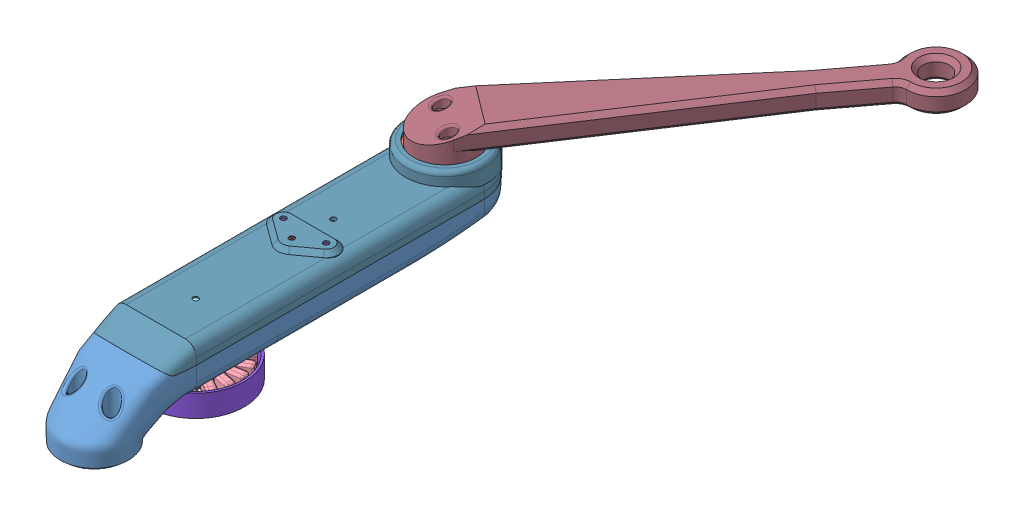
SolidWorks assembly Detailed upper leg module assembly new, configuration Default. Lengths in mm.
Overall size (146.19 56.44 322.34).
28 component instances, 17 part files, 42 mates.
Components (placement in the parent):
- upper limb base-1: upper limb base [Default] at (70.7092 92.7911 149.0007) size (42.52 37.51 198.25)
  - upper leg module shell base-1: upper leg module shell base [Default] x (-1 0 0) z (0 0 -1) size (37.02 37.51 198.25)
  - bearing 32x25x4mm-1: bearing 32x25x4mm [Default] at (0 0.5 -61) x (0.90658 0 0.422034) z (-0.422034 0 0.90658) size (32 4 32)
  - bearing 8mm x 3mm x 3mm-1: bearing 8mm x 3mm x 3mm [Default] at (0 -1.5 8.9) x (1 0 0) z (0 -1 0) size (7.96 7.96 3)
- motor rotor-1: motor rotor [Default] at (70.7092 85.0911 201.8007) x (0 0 -1) z (-1 0 0) size (40 13.5 39.72)
- motor assembly-2: motor assembly [Default] at (70.7092 72.4911 201.8007) x (-0.761097 0 -0.648639) z (-0.648639 0 0.761097) size (16.67 33.4 16.67)
  - motor shaft-1: motor shaft [Default] x (1 0 0) z (0 -1 0) size (3.99 3.99 33.4)
  - motor pulley-1: motor pulley [Default] at (0 -20.1 0) x (1 0 0) z (0 -1 0) size (8.98 9.1 6.7)
  - encoder wheel mount-1: encoder wheel mount [Default] at (0 -28.3 0) x (-0.562764 0 0.826618) z (-0.826618 0 -0.562764) size (12 5.96 12)
- motor stator-1: motor stator [Default] at (70.7092 85.0911 201.8007) x (0.629554 0 -0.776957) z (0 -1 0) size (44.35 44.35 16.24)
- B18.6.7M - M3 x 0.5 x 5 Type I Cross Recessed FHMS --5S-1: B18.6.7M - M3 x 0.5 x 5 Type I Cross Recessed FHMS --5S [B18.6.7M - M3 x 0.5 x 5 Type I Cross Recessed FHMS --5S] at (83.2092 94.5911 201.8007) x (0 -1 0) z (-0.166423 0 0.986054) size (5 5.5 5.5)
- B18.6.7M - M3 x 0.5 x 5 Type I Cross Recessed FHMS --5S-2: B18.6.7M - M3 x 0.5 x 5 Type I Cross Recessed FHMS --5S [B18.6.7M - M3 x 0.5 x 5 Type I Cross Recessed FHMS --5S] at (70.7092 94.5911 214.3007) x (0 -1 0) z (0.029806 0 0.999556) size (5 5.5 5.5)
- B18.6.7M - M3 x 0.5 x 5 Type I Cross Recessed FHMS --5S-3: B18.6.7M - M3 x 0.5 x 5 Type I Cross Recessed FHMS --5S [B18.6.7M - M3 x 0.5 x 5 Type I Cross Recessed FHMS --5S] at (58.2092 94.5911 201.8007) x (0 -1 0) z (0.999629 0 -0.027231) size (5 5.5 5.5)
- B18.6.7M - M3 x 0.5 x 5 Type I Cross Recessed FHMS --5S-4: B18.6.7M - M3 x 0.5 x 5 Type I Cross Recessed FHMS --5S [B18.6.7M - M3 x 0.5 x 5 Type I Cross Recessed FHMS --5S] at (70.7092 94.5911 189.3007) x (0 -1 0) z (-0.93368 0 0.358107) size (5 5.5 5.5)
- centre pulley-1: centre pulley [Default] at (66.4357 80.4446 131.9015) x (0.990944 0 0.134278) z (-0.134278 0 0.990944) size (30 19 30)
  - transmission pulley centre-1: transmission pulley centre [Default] at (7.726 11.8465 25.1899) size (30 6.8 30)
  - centre pulley-1: centre pulley [Default] at (7.726 25.3465 25.1899) x (0.694658 0 -0.71934) z (0 -1 0) size (8.98 9.1 19)
- transmission pulley output-1: transmission pulley output [Default] at (70.7092 97.7911 88.0007) x (-0.799532 0 -0.600624) z (0.600624 0 -0.799532) size (29 16.4 29)
- lower leg-1: lower leg [Default] at (118.7591 125.2911 24.0382) x (0.600624 0 -0.799532) z (-0.799532 0 -0.600624) size (187 20 27)
- upper leg module cover-1: upper leg module cover [Default] at (70.7092 98.7911 142.6299) x (0 0 1) z (-1 0 0) size (170.23 17.96 37.06)
- bearing 32x25x4mm-1: bearing 32x25x4mm [Default] at (70.7092 107.2911 88.0007) size (32 4 32)
- bearing 8mm x 3mm x 3mm-1: bearing 8mm x 3mm x 3mm [Default] at (70.7092 107.2911 157.9007) x (1 0 0) z (0 -1 0) size (7.96 7.96 3)
- transmission belt tension roller-1: transmission belt tension roller [Default] at (60.9592 99.8911 152.0007) x (0.454066 0 0.890968) z (-0.890968 0 0.454066) size (10 4 10)
- bearing 7mm x 3mm x 3mm-2: bearing 7mm x 3mm x 3mm [Default] at (60.9592 103.8911 152.0007) x (0.030533 0 0.999534) z (0 -1 0) size (7 7 3)
- transmission belt tension roller-2: transmission belt tension roller [Default] at (80.4592 99.8911 152.0007) x (0.177081 0 -0.984196) z (0.984196 0 0.177081) size (10 4 10)
- bearing 7mm x 3mm x 3mm-3: bearing 7mm x 3mm x 3mm [Default] at (80.4592 103.8911 152.0007) x (0 0 -1) z (0 -1 0) size (7 7 3)
- flat head screw_am-1: flat head screw_am [B18.6.7M - M3 x 0.5 x 8 Type I Cross Recessed FHMS --8S] at (60.9592 100.0411 152.0007) x (0 1 0) z (0.851744 0 -0.523958) size (8 5.5 5.5)
- flat head screw_am-2: flat head screw_am [B18.6.7M - M3 x 0.5 x 8 Type I Cross Recessed FHMS --8S] at (80.4592 100.0411 152.0007) x (0 1 0) z (0.851744 0 -0.523958) size (8 5.5 5.5)
Mates (geometry in assembly coordinates):
- Concentric1: concentric aligned: cylinder of upper limb base-1/upper leg module shell base-1 through (70.7092 93.0911 201.8007) axis (0 -1 0) radius 15.25; cylinder of motor rotor-1 through (70.7092 92.5911 201.8007) axis (0 -1 0) radius 15
- Concentric2: concentric anti-aligned: cylinder of upper limb base-1/upper leg module shell base-1 through (70.7092 64.5911 189.3007) axis (0 1 0) radius 1.6; cylinder of motor rotor-1 through (70.7092 92.5911 189.3007) axis (0 -1 0) radius 2
- Coincident1: coincident anti-aligned: plane of upper limb base-1/upper leg module shell base-1 through (70.7092 92.5911 201.8007) normal (0 -1 0); plane of motor rotor-1 through (70.7092 92.5911 201.8007) normal (0 1 0)
- Concentric3: concentric aligned: line of motor rotor-1 through (70.7092 92.5911 201.8007) axis (0 -1 0); cylinder of motor assembly-2/motor shaft-1 through (70.7092 105.8911 201.8007) axis (0 -1 0) radius 1.995
- Coincident2: coincident anti-aligned: plane of motor rotor-1 through (70.7092 92.5911 201.8007) normal (0 1 0); plane of motor assembly-2/motor pulley-1 through (70.7092 92.5911 201.8007) normal (0 -1 0)
- Concentric4: concentric aligned: cylinder of motor assembly-2/motor shaft-1 through (70.7092 105.8911 201.8007) axis (0 -1 0) radius 1.995; cylinder of motor stator-1 through (70.7092 75.0911 201.8007) axis (0 -1 0) radius 2
- Coincident3: coincident aligned: plane of motor rotor-1 through (70.7092 85.0911 201.8007) normal (0 1 0); plane of motor stator-1 through (70.7092 85.0911 201.8007) normal (0 1 0)
- Concentric5: concentric anti-aligned: cylinder of motor rotor-1 through (70.7092 92.5911 189.3007) axis (0 -1 0) radius 2; cylinder of B18.6.7M - M3 x 0.5 x 5 Type I Cross Recessed FHMS --5S-4 through (70.7092 100.9411 189.3007) axis (0 1 0) radius 1.5
- Concentric6: concentric anti-aligned: cylinder of motor rotor-1 through (58.2092 92.5911 201.8007) axis (0 -1 0) radius 2; cylinder of B18.6.7M - M3 x 0.5 x 5 Type I Cross Recessed FHMS --5S-3 through (58.2092 100.9411 201.8007) axis (0 1 0) radius 1.5
- Concentric7: concentric anti-aligned: cylinder of motor rotor-1 through (70.7092 92.5911 214.3007) axis (0 -1 0) radius 2; cylinder of B18.6.7M - M3 x 0.5 x 5 Type I Cross Recessed FHMS --5S-2 through (70.7092 100.9411 214.3007) axis (0 1 0) radius 1.5
- Concentric8: concentric anti-aligned: cylinder of motor rotor-1 through (83.2092 92.5911 201.8007) axis (0 -1 0) radius 2; cylinder of B18.6.7M - M3 x 0.5 x 5 Type I Cross Recessed FHMS --5S-1 through (83.2092 100.9411 201.8007) axis (0 1 0) radius 1.5
- Coincident4: coincident aligned: plane of upper limb base-1/upper leg module shell base-1 through (70.7092 94.5911 201.8007) normal (0 1 0); plane of B18.6.7M - M3 x 0.5 x 5 Type I Cross Recessed FHMS --5S-4 through (70.7092 94.5911 189.3007) normal (0 1 0)
- Coincident5: coincident aligned: plane of upper limb base-1/upper leg module shell base-1 through (70.7092 94.5911 201.8007) normal (0 1 0); plane of B18.6.7M - M3 x 0.5 x 5 Type I Cross Recessed FHMS --5S-3 through (58.2092 94.5911 201.8007) normal (0 1 0)
- Coincident6: coincident aligned: plane of upper limb base-1/upper leg module shell base-1 through (70.7092 94.5911 201.8007) normal (0 1 0); plane of B18.6.7M - M3 x 0.5 x 5 Type I Cross Recessed FHMS --5S-1 through (83.2092 94.5911 201.8007) normal (0 1 0)
- Coincident7: coincident aligned: plane of upper limb base-1/upper leg module shell base-1 through (70.7092 94.5911 201.8007) normal (0 1 0); plane of B18.6.7M - M3 x 0.5 x 5 Type I Cross Recessed FHMS --5S-2 through (70.7092 94.5911 214.3007) normal (0 1 0)
- Concentric9: concentric anti-aligned: line of upper limb base-1/bearing 8mm x 3mm x 3mm-1 through (70.7092 91.0911 157.9007) axis (0 -1 0); cylinder of centre pulley-1/centre pulley-1 through (70.7092 89.2911 157.9007) axis (0 1 0) radius 1.995
- Coincident9: coincident anti-aligned: plane of upper limb base-1/bearing 8mm x 3mm x 3mm-1 through (70.7092 91.2911 157.9007) normal (0 1 0); plane of centre pulley-1/centre pulley-1 through (70.7092 91.2911 157.9007) normal (0 -1 0)
- Concentric11: concentric anti-aligned: cylinder of upper limb base-1/bearing 32x25x4mm-1 through (70.7092 97.2911 88.0007) axis (0 -1 0) radius 12.5; cylinder of transmission pulley output-1 through (70.7092 93.4411 88.0007) axis (0 1 0) radius 12.575
- Coincident12: coincident anti-aligned: plane of upper limb base-1/bearing 32x25x4mm-1 through (70.7092 97.2911 88.0007) normal (0 1 0); plane of transmission pulley output-1 through (70.7092 97.2911 88.0007) normal (0 -1 0)
- Coincident18: coincident anti-aligned: plane of transmission pulley output-1 through (80.1125 93.4411 83.808) normal (-0.799532 0 -0.600624); plane of lower leg-1 through (70.2022 105.2911 97.0003) normal (0.799532 0 0.600624)
- Coincident19: coincident anti-aligned: plane of transmission pulley output-1 through (61.3059 93.4411 92.1934) normal (0.600624 0 -0.799532); plane of lower leg-1 through (62.5052 105.2911 93.0943) normal (-0.600624 0 0.799532)
- Concentric12: concentric aligned: circle of upper limb base-1/bearing 32x25x4mm-1; cylinder of upper leg module cover-1 through (70.7092 87.7911 88.0007) axis (0 1 0) radius 14.25
- Coincident20: coincident aligned: plane of upper limb base-1/upper leg module shell base-1 through (89.2092 86.7911 109.0007) normal (1 0 0); plane of upper leg module cover-1 through (89.2092 106.7911 219.9999) normal (1 0 0)
- Coincident24: coincident anti-aligned: plane of upper leg module cover-1 through (70.7092 107.2911 157.9007) normal (0 -1 0); plane of bearing 8mm x 3mm x 3mm-1 through (70.7092 107.2911 157.9007) normal (0 1 0)
- Concentric16: concentric anti-aligned: cylinder of upper leg module cover-1 through (70.7092 107.2911 157.9007) axis (0 -1 0) radius 3.98; cylinder of bearing 8mm x 3mm x 3mm-1 through (70.7092 104.2911 157.9007) axis (0 1 0) radius 3.98
- Concentric17: concentric anti-aligned: cylinder of upper leg module cover-1 through (70.7092 100.7911 88.0007) axis (0 1 0) radius 16.4954; cylinder of bearing 32x25x4mm-1 through (70.7092 111.2911 88.0007) axis (0 -1 0) radius 16
- Coincident25: coincident anti-aligned: plane of upper leg module cover-1 through (70.7092 111.2911 88.0007) normal (0 -1 0); plane of bearing 32x25x4mm-1 through (70.7092 111.2911 88.0007) normal (0 1 0)
- Coincident27: coincident anti-aligned: plane of transmission pulley output-1 through (72.1172 93.4411 77.8018) normal (0.799532 0 0.600624); plane of lower leg-1 through (62.2069 105.2911 90.9941) normal (-0.799532 0 -0.600624)
- Coincident28: coincident anti-aligned: plane of lower leg-1 through (70.7092 111.2911 88.0007) normal (0 -1 0); plane of bearing 32x25x4mm-1 through (70.7092 111.2911 88.0007) normal (0 1 0)
- Concentric18: concentric anti-aligned: cylinder of transmission belt tension roller-1 through (60.9592 103.8911 152.0007) axis (0 -1 0) radius 3.5; cylinder of bearing 7mm x 3mm x 3mm-2 through (60.9592 100.8911 152.0007) axis (0 1 0) radius 3.5
- Coincident29: coincident anti-aligned: plane of transmission belt tension roller-1 through (60.9592 100.8911 152.0007) normal (0 1 0); plane of bearing 7mm x 3mm x 3mm-2 through (60.9592 100.8911 152.0007) normal (0 -1 0)
- Coincident30: coincident anti-aligned: plane of upper leg module cover-1 through (60.9592 103.8911 152.0007) normal (0 -1 0); plane of transmission belt tension roller-1 through (60.9592 103.8911 152.0007) normal (0 1 0)
- Concentric19: concentric anti-aligned: cylinder of upper leg module cover-1 through (60.9592 103.8911 152.0007) axis (0 1 0) radius 4; cylinder of transmission belt tension roller-1 through (60.9592 103.8911 152.0007) axis (0 -1 0) radius 5
- Concentric20: concentric anti-aligned: cylinder of transmission belt tension roller-2 through (80.4592 103.8911 152.0007) axis (0 -1 0) radius 3.5; cylinder of bearing 7mm x 3mm x 3mm-3 through (80.4592 100.8911 152.0007) axis (0 1 0) radius 3.5
- Coincident31: coincident anti-aligned: plane of transmission belt tension roller-2 through (80.4592 100.8911 152.0007) normal (0 1 0); plane of bearing 7mm x 3mm x 3mm-3 through (80.4592 100.8911 152.0007) normal (0 -1 0)
- Coincident33: coincident anti-aligned: plane of upper leg module cover-1 through (80.4592 103.8911 152.0007) normal (0 -1 0); plane of bearing 7mm x 3mm x 3mm-3 through (80.4592 103.8911 152.0007) normal (0 1 0)
- Concentric22: concentric anti-aligned: cylinder of upper leg module cover-1 through (80.4592 103.8911 152.0007) axis (0 1 0) radius 4; cylinder of transmission belt tension roller-2 through (80.4592 103.8911 152.0007) axis (0 -1 0) radius 5
- Concentric23: concentric anti-aligned: cylinder of bearing 7mm x 3mm x 3mm-2 through (60.9592 100.8911 152.0007) axis (0 1 0) radius 1.5; cylinder of flat head screw_am-1 through (60.9592 93.6911 152.0007) axis (0 -1 0) radius 1.5
- Coincident34: coincident aligned: cone of transmission belt tension roller-1 through (60.9592 100.4911 152.0007) axis (0 1 0); cone of flat head screw_am-1 through (60.9592 100.4911 152.0007) axis (0 1 0)
- Concentric24: concentric anti-aligned: cylinder of bearing 7mm x 3mm x 3mm-3 through (80.4592 100.8911 152.0007) axis (0 1 0) radius 1.5; cylinder of flat head screw_am-2 through (80.4592 93.6911 152.0007) axis (0 -1 0) radius 1.5
- Coincident35: coincident aligned: cone of transmission belt tension roller-2 through (80.4592 100.4911 152.0007) axis (0 1 0); cone of flat head screw_am-2 through (80.4592 100.4911 152.0007) axis (0 1 0)
- Coincident36: coincident anti-aligned: plane of upper limb base-1/upper leg module shell base-1 through (52.2092 98.7911 109.0007) normal (0 1 0); plane of upper leg module cover-1 through (70.7092 98.7911 142.6299) normal (0 -1 0)
